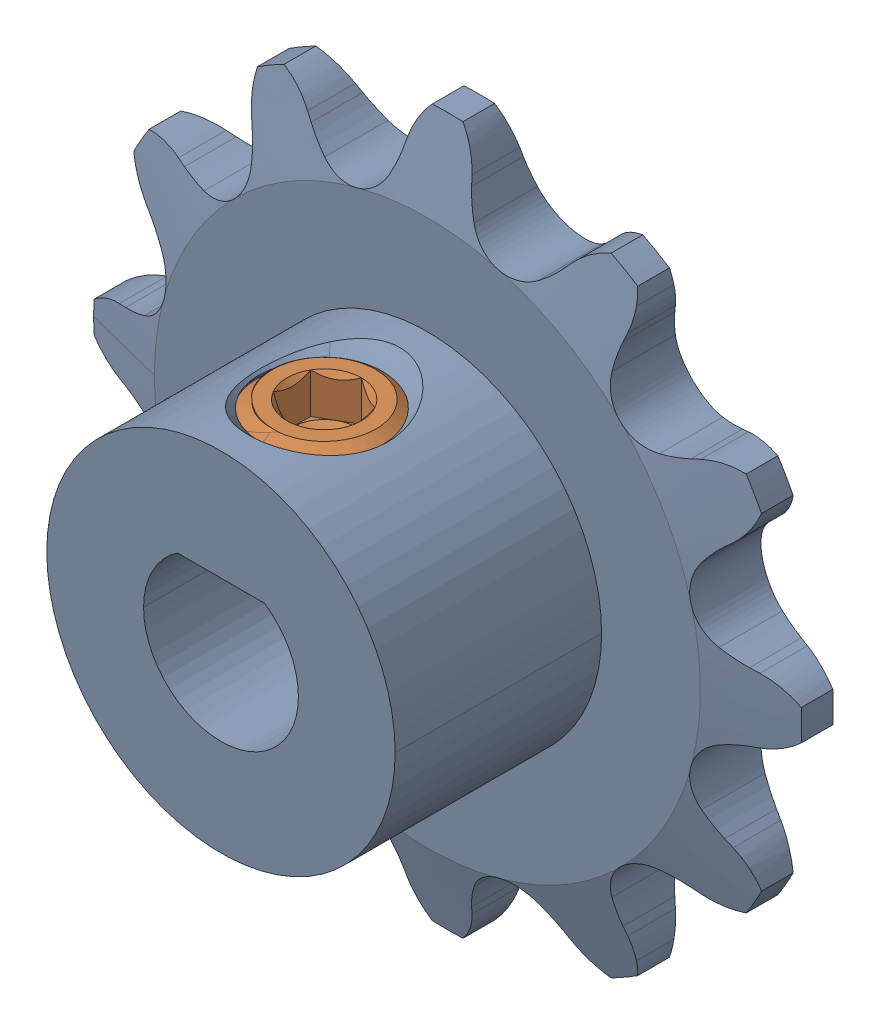
SolidWorks assembly 3304-1006-0012 assembly.STEP, configuration Default. Lengths in mm.
Overall size (27.43 27.43 10.94).
2 component instances, 2 part files, 0 mates.
Components (placement in the parent):
- 3304-1006-0012.STEP-1: 3304-1006-0012.STEP [Default] at (-36.7101 -2.0252 16.7473) size (27.43 27.43 10.94)
- 2806-0005-0004_91390A117.STEP-1: 2806-0005-0004_91390A117.STEP [Default] at (-36.7101 2.8664 22.1443) x (1 0 0) z (0 1 0) size (5.01 5.01 4.01)
